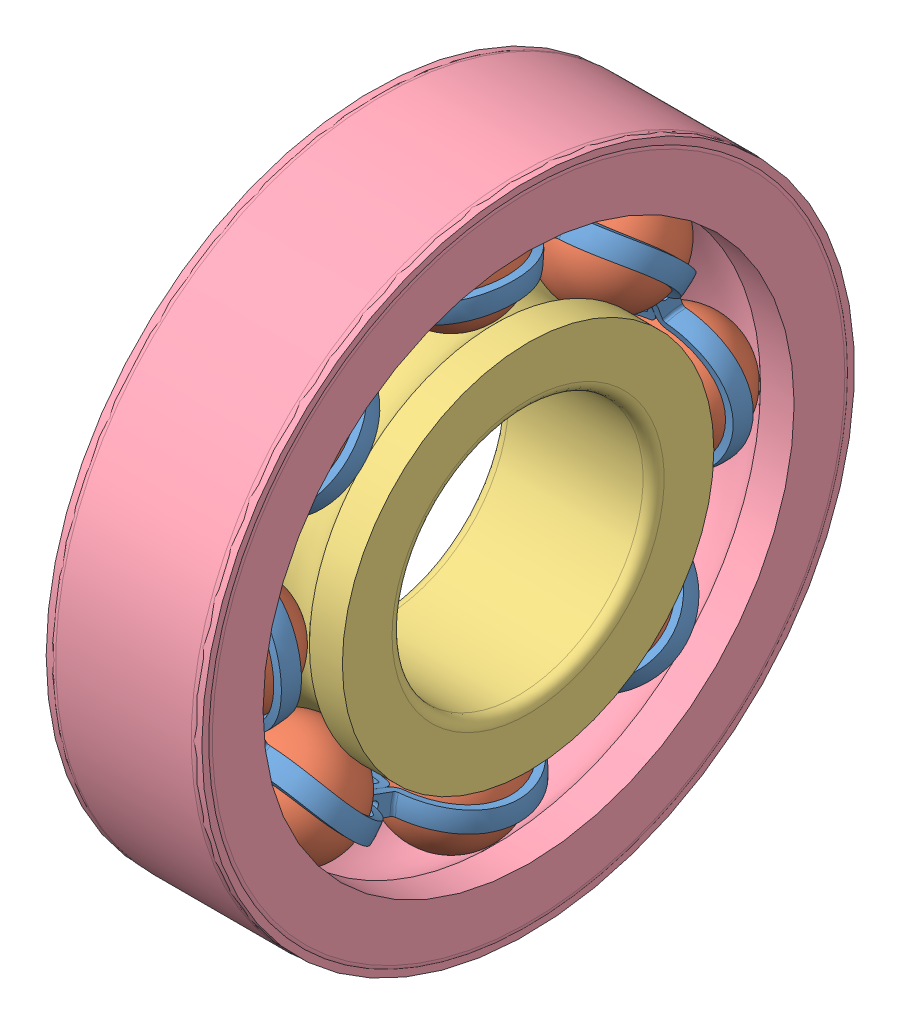
SolidWorks assembly Ball Bearing ASSEMBLY, configuration Default. Lengths in mm.
Overall size (792.48 3307.08 3307.08).
12 component instances, 4 part files, 8 mates.
Components (placement in the parent):
- Ball Bearing Cage-2: Ball Bearing Cage [Default] at (-2050.7508 2130.2566 -2007.3019) x (0 0.999954 0.009553) z (0 -0.009553 0.999954) size (2387.6 346.65 2387.6)
- Ball of Ball Bearing-2: Ball of Ball Bearing [Default] at (-2253.9491 3273.2566 -2007.3019) size (609.6 587.76 587.76)
- Inner ring of Ball Bearing-2: Inner ring of Ball Bearing [Default] at (-2253.9491 2130.2566 -2007.3019) size (787.4 1879.6 1879.6)
- Outer ring of Ball Bearing-2: Outer ring of Ball Bearing [Default] at (-2253.9491 2130.2566 -2010.1339) size (792.48 3307.08 3307.08)
- Ball of Ball Bearing-3: Ball of Ball Bearing [Default] at (-2253.9491 2938.4796 -2815.525) x (1 0 0) z (0 0.707107 0.707107) size (609.6 587.76 587.76)
- Ball of Ball Bearing-4: Ball of Ball Bearing [Default] at (-2253.9491 2130.2566 -3150.3019) x (1 0 0) z (0 1 0) size (609.6 587.76 587.76)
- Ball of Ball Bearing-5: Ball of Ball Bearing [Default] at (-2253.9491 1322.0335 -2815.525) x (1 0 0) z (0 0.707107 -0.707107) size (609.6 587.76 587.76)
- Ball of Ball Bearing-6: Ball of Ball Bearing [Default] at (-2253.9491 987.2566 -2007.3019) x (1 0 0) z (0 0 -1) size (609.6 587.76 587.76)
- Ball of Ball Bearing-7: Ball of Ball Bearing [Default] at (-2253.9491 1322.0335 -1199.0789) x (1 0 0) z (0 -0.707107 -0.707107) size (609.6 587.76 587.76)
- Ball of Ball Bearing-8: Ball of Ball Bearing [Default] at (-2253.9491 2130.2566 -864.3019) x (1 0 0) z (0 -1 0) size (609.6 587.76 587.76)
- Ball of Ball Bearing-9: Ball of Ball Bearing [Default] at (-2253.9491 2938.4796 -1199.0789) x (1 0 0) z (0 -0.707107 0.707107) size (609.6 587.76 587.76)
- Ball Bearing Cage-3: Ball Bearing Cage [Default] at (-2457.1508 2130.2566 -2007.3019) x (0 0.999954 0.009553) z (0 0.009553 -0.999954) size (2387.6 346.65 2387.6)
Mates (geometry in assembly coordinates):
- Concentric1: concentric aligned: cylinder of Inner ring of Ball Bearing-2 through (-2840.5621 2130.2566 -2007.3019) axis (-1 0 0) radius 635; cylinder of Outer ring of Ball Bearing-2 through (-2652.5717 2130.2566 -2007.3019) axis (-1 0 0) radius 1653.54
- Width1: width aligned: plane of Outer ring of Ball Bearing-2 through (-1857.7091 2130.2566 -2010.1339) normal (1 0 0); plane of Inner ring of Ball Bearing-2 through (-2650.1891 2130.2566 -2010.1339) normal (-1 0 0); plane of Outer ring of Ball Bearing-2 through (-1860.2491 2130.2566 -2695.6419) normal (1 0 0); plane of Inner ring of Ball Bearing-2 through (-2647.6491 2130.2566 -2695.6419) normal (-1 0 0)
- Coincident13: coincident aligned: plane of Ball of Ball Bearing-2 through (-2253.9491 3273.2566 -2007.3019) normal (1 0 0); plane of Inner ring of Ball Bearing-2 through (-2253.9491 2130.2566 -2007.3019) normal (1 0 0)
- Coincident16: coincident aligned: plane of Ball of Ball Bearing-2 through (-2253.9491 3273.2566 -2007.3019) normal (0 0 1); plane of Inner ring of Ball Bearing-2 through (-2253.9491 2130.2566 -2007.3019) normal (0 0 1)
- Coincident17: coincident aligned: plane of Ball of Ball Bearing-2 through (-2253.9491 3273.2566 -2007.3019) normal (1 0 0); plane of Inner ring of Ball Bearing-2 through (-2253.9491 2130.2566 -2007.3019) normal (1 0 0)
- Distance2: distance = 1143 mm aligned: plane of Ball of Ball Bearing-2 through (-2253.9491 3273.2566 -2007.3019) normal (0 1 0); plane of Inner ring of Ball Bearing-2 through (-2253.9491 2130.2566 -2007.3019) normal (0 1 0)
- Coincident24: coincident anti-aligned: line of Ball Bearing Cage-2 through (-2253.9508 2130.2566 -2007.3019) axis (1 0 0); line of Inner ring of Ball Bearing-2 through (-1714.6072 2130.2566 -2007.3019) axis (-1 0 0)
- Tangent5: tangent aligned: sphere of Ball Bearing Cage-2; torus of Ball of Ball Bearing-9
